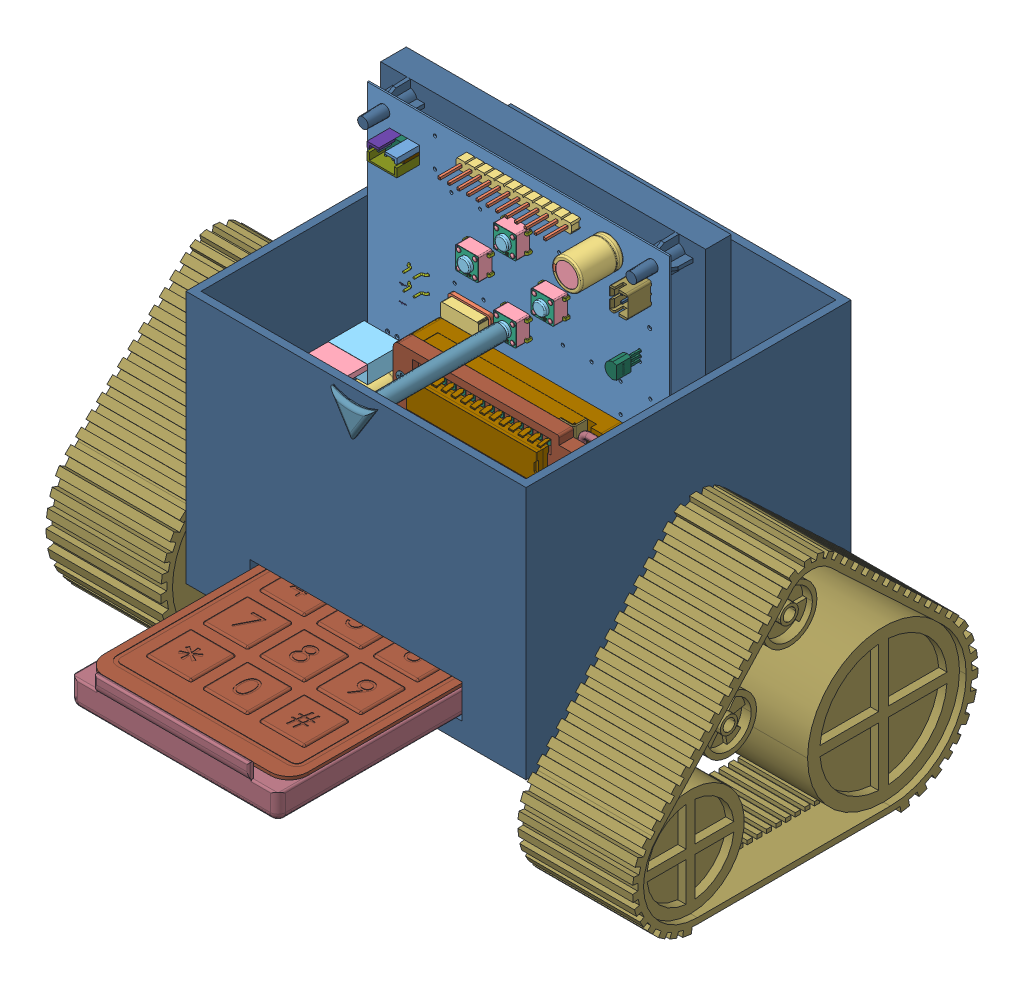
SolidWorks assembly Initial, configuration Default. Lengths in mm.
Overall size (155.25 120.58 135.91).
171 component instances, 50 part files, 12 mates.
Components (placement in the parent):
- Clock PCB.step-1: Clock PCB.step [Default] at (-3.837 -6.133 58.5856) size (81.95 80 25.5)
  - Board.step-1: Board.step [Default] at origin size (80 80 0.41)
    - Open CASCADE STEP translator 6.8 1.1.1.step-1: Open CASCADE STEP translator 6.8 1.1.1.step [Default] at (0 0 -0.4115) size (80 80 0.41)
  - XTAL1.step-1: XTAL1.step [Default] at origin size (11.36 4.66 3.61)
    - 6606830048.step-1: 6606830048.step [Default] at (28.0499 41.0499 0) size (11.36 4.66 1.01)
      - Extruded.step-1: Extruded.step [Default] at origin size (11.36 4.66 1.01)
    - 6606829968.step-1: 6606829968.step [Default] at (28.0499 41.0501 1) size (10.05 3.71 2.61)
      - Extruded-0.step-1: Extruded-0.step [Default] at origin size (10.05 3.71 2.61)
  - U2.step-1: U2.step [Default] at origin size (10.5 4.7 16.2)
    - 6606829888.step-1: 6606829888.step [Default] at (7.95 27.55 13.05) size (10.4 1.3 6.65)
      - Extruded-1.step-1: Extruded-1.step [Default] at origin size (10.4 1.3 6.65)
    - 6606829728.step-1: 6606829728.step [Default] at (7.95 25.9 3.5) size (10.5 4.7 9.55)
      - Extruded-2.step-1: Extruded-2.step [Default] at origin size (10.5 4.7 9.55)
  - U1.step-1: U1.step [Default] at origin size (63.7 16.03 14.45)
    - User_Library-ZIF-Socket-28-pin.step-1: User_Library-ZIF-Socket-28-pin.step [Default] at (43.5 28.05 0) x (1 0 0) z (0 0 1) size (63.7 16.03 14.45)
      - Contacts.step-1: Contacts.step [Default] at origin size (34.37 11.24 1.5)
      - Pins001.step-1: Pins001.step [Default] at origin size (33.87 8.47 3)
      - Screw002.step-1: Screw002.step [Default] at origin size (2.8 2.8 2)
      - Bottom-Shape.step-1: Bottom-Shape.step [Default] at origin size (50.4 15.02 8.11)
      - Lever-Tip.step-1: Lever-Tip.step [Default] at origin size (7 4.8 4.8)
      - Top-Shape.step-1: Top-Shape.step [Default] at origin size (50.4 15.02 3.8)
      - Push-Bar.step-1: Push-Bar.step [Default] at origin size (3.85 15.02 3.7)
      - Lever-Bar.step-1: Lever-Bar.step [Default] at origin size (19.2 11.43 1.62)
      - Screw001.step-1: Screw001.step [Default] at origin size (2.8 2.8 2)
  - Q1.step-1: Q1.step [Default] at origin size (3.05 4.08 12.8)
    - BC547-B.step-1: BC547-B.step [Default] at (72 53.1536 7) x (0 1 0) z (0 0 -1) size (4.08 3.05 12.8)
  - P3.step-1: P3.step [Default] at origin size (2.54 10.16 11.54)
    - 61300411121.step-1: 61300411121.step [Default] at (76.2999 22.6001 1.3) x (0 1 0) z (1 0 0) size (10.16 11.54 2.54)
      - 6130xx11121_PIN.step-1: 6130xx11121_PIN.step [Default] at (-3.81 1.5 0) x (1 0 0) z (0 -1 0) size (0.64 0.64 11.54)
      - 6130xx11121_PIN.step-2: 6130xx11121_PIN.step [Default] at (-1.27 1.5 0) x (1 0 0) z (0 -1 0) size (0.64 0.64 11.54)
      - 6130xx11121_PIN.step-3: 6130xx11121_PIN.step [Default] at (1.27 1.5 0) x (1 0 0) z (0 -1 0) size (0.64 0.64 11.54)
      - 6130xx11121_PIN.step-4: 6130xx11121_PIN.step [Default] at (3.81 1.5 0) x (1 0 0) z (0 -1 0) size (0.64 0.64 11.54)
      - 61300411121-3.step-1: 61300411121-3.step [Default] at origin size (10.16 2.54 2.54)
  - P2.step-1: P2.step [Default] at origin size (17.78 2.54 11.54)
    - 61300711121.step-1: 61300711121.step [Default] at (39.9599 3.8999 1.3) x (-1 0 0) z (0 1 0) size (17.78 11.54 2.54)
      - 6130xx11121_PIN-4.step-1: 6130xx11121_PIN-4.step [Default] at (-7.62 1.5 0) x (1 0 0) z (0 -1 0) size (0.64 0.64 11.54)
      - 6130xx11121_PIN-4.step-2: 6130xx11121_PIN-4.step [Default] at (-5.08 1.5 0) x (1 0 0) z (0 -1 0) size (0.64 0.64 11.54)
      - 6130xx11121_PIN-4.step-3: 6130xx11121_PIN-4.step [Default] at (-2.54 1.5 0) x (1 0 0) z (0 -1 0) size (0.64 0.64 11.54)
      - 6130xx11121_PIN-4.step-4: 6130xx11121_PIN-4.step [Default] at (0 1.5 0) x (1 0 0) z (0 -1 0) size (0.64 0.64 11.54)
      - 6130xx11121_PIN-4.step-5: 6130xx11121_PIN-4.step [Default] at (2.54 1.5 0) x (1 0 0) z (0 -1 0) size (0.64 0.64 11.54)
      - 6130xx11121_PIN-4.step-6: 6130xx11121_PIN-4.step [Default] at (5.08 1.5 0) x (1 0 0) z (0 -1 0) size (0.64 0.64 11.54)
      - 6130xx11121_PIN-4.step-7: 6130xx11121_PIN-4.step [Default] at (7.62 1.5 0) x (1 0 0) z (0 -1 0) size (0.64 0.64 11.54)
      - 61300711121-5.step-1: 61300711121-5.step [Default] at origin size (17.78 2.54 2.54)
  - P1.step-1: P1.step [Default] at origin size (30.48 2.54 11.54)
    - 61301211121.step-1: 61301211121.step [Default] at (41.3799 75.6999 1.3) x (-1 0 0) z (0 1 0) size (30.48 11.54 2.54)
      - 6130xx11121_PIN-6.step-1: 6130xx11121_PIN-6.step [Default] at (-13.97 1.5 0) x (1 0 0) z (0 -1 0) size (0.64 0.64 11.54)
      - 6130xx11121_PIN-6.step-2: 6130xx11121_PIN-6.step [Default] at (-11.43 1.5 0) x (1 0 0) z (0 -1 0) size (0.64 0.64 11.54)
      - 6130xx11121_PIN-6.step-3: 6130xx11121_PIN-6.step [Default] at (-8.89 1.5 0) x (1 0 0) z (0 -1 0) size (0.64 0.64 11.54)
      - 6130xx11121_PIN-6.step-4: 6130xx11121_PIN-6.step [Default] at (-6.35 1.5 0) x (1 0 0) z (0 -1 0) size (0.64 0.64 11.54)
      - 6130xx11121_PIN-6.step-5: 6130xx11121_PIN-6.step [Default] at (-3.81 1.5 0) x (1 0 0) z (0 -1 0) size (0.64 0.64 11.54)
      - 6130xx11121_PIN-6.step-6: 6130xx11121_PIN-6.step [Default] at (-1.27 1.5 0) x (1 0 0) z (0 -1 0) size (0.64 0.64 11.54)
      - 6130xx11121_PIN-6.step-7: 6130xx11121_PIN-6.step [Default] at (1.27 1.5 0) x (1 0 0) z (0 -1 0) size (0.64 0.64 11.54)
      - 6130xx11121_PIN-6.step-8: 6130xx11121_PIN-6.step [Default] at (3.81 1.5 0) x (1 0 0) z (0 -1 0) size (0.64 0.64 11.54)
      - 6130xx11121_PIN-6.step-9: 6130xx11121_PIN-6.step [Default] at (6.35 1.5 0) x (1 0 0) z (0 -1 0) size (0.64 0.64 11.54)
      - 6130xx11121_PIN-6.step-10: 6130xx11121_PIN-6.step [Default] at (8.89 1.5 0) x (1 0 0) z (0 -1 0) size (0.64 0.64 11.54)
      - 6130xx11121_PIN-6.step-11: 6130xx11121_PIN-6.step [Default] at (11.43 1.5 0) x (1 0 0) z (0 -1 0) size (0.64 0.64 11.54)
      - 6130xx11121_PIN-6.step-12: 6130xx11121_PIN-6.step [Default] at (13.97 1.5 0) x (1 0 0) z (0 -1 0) size (0.64 0.64 11.54)
      - 61301211121-7.step-1: 61301211121-7.step [Default] at origin size (30.48 2.54 2.54)
  - KEY5.step-1: KEY5.step [Default] at origin size (7.8 5.99 8.11)
    - Switch_TE_1825910-2_eec.step-1: Switch_TE_1825910-2_eec.step [Default] at (68.1 13.85 0) size (7.8 5.99 8.11)
      - Body.step-1: Body.step [Default] at (0 0 4.3) x (0 -1 0) z (0 0 1) size (5.99 5.99 3.9)
      - button.step-1: button.step [Default] at (0 0 4.3) x (0 -1 0) z (0 0 1) size (3.51 3.51 1.1)
      - cover.step-1: cover.step [Default] at (0 0 4.3) x (0 -1 0) z (0 0 1) size (5.99 5.99 0.1)
      - leads.step-1: leads.step [Default] at (0 0 4.3) x (0 -1 0) z (0 0 1) size (5.21 7.8 4.81)
      - circle.step-1: circle.step [Default] at (-2.6803 2.6863 3.6) size (0.4 0.4 0)
      - TE_Connectivity.step-1: TE_Connectivity.step [Default] at (-0.1925 -2.4218 3.6) size (2.27 0.85 0.01)
  - KEY4.step-1: KEY4.step [Default] at origin size (7.8 5.99 8.11)
    - Switch_TE_1825910-2_eec.step-1: Switch_TE_1825910-2_eec.step [Default] at (50 55 0) size (7.8 5.99 8.11)
      - Body.step-1: Body.step [Default] at (0 0 4.3) x (0 -1 0) z (0 0 1) size (5.99 5.99 3.9)
      - button.step-1: button.step [Default] at (0 0 4.3) x (0 -1 0) z (0 0 1) size (3.51 3.51 1.1)
      - cover.step-1: cover.step [Default] at (0 0 4.3) x (0 -1 0) z (0 0 1) size (5.99 5.99 0.1)
      - leads.step-1: leads.step [Default] at (0 0 4.3) x (0 -1 0) z (0 0 1) size (5.21 7.8 4.81)
      - circle.step-1: circle.step [Default] at (-2.6803 2.6863 3.6) size (0.4 0.4 0)
      - TE_Connectivity.step-1: TE_Connectivity.step [Default] at (-0.1925 -2.4218 3.6) size (2.27 0.85 0.01)
  - KEY3.step-1: KEY3.step [Default] at origin size (7.8 5.99 8.11)
    - Switch_TE_1825910-2_eec.step-1: Switch_TE_1825910-2_eec.step [Default] at (30 55 0) size (7.8 5.99 8.11)
      - Body.step-1: Body.step [Default] at (0 0 4.3) x (0 -1 0) z (0 0 1) size (5.99 5.99 3.9)
      - button.step-1: button.step [Default] at (0 0 4.3) x (0 -1 0) z (0 0 1) size (3.51 3.51 1.1)
      - cover.step-1: cover.step [Default] at (0 0 4.3) x (0 -1 0) z (0 0 1) size (5.99 5.99 0.1)
      - leads.step-1: leads.step [Default] at (0 0 4.3) x (0 -1 0) z (0 0 1) size (5.21 7.8 4.81)
      - circle.step-1: circle.step [Default] at (-2.6803 2.6863 3.6) size (0.4 0.4 0)
      - TE_Connectivity.step-1: TE_Connectivity.step [Default] at (-0.1925 -2.4218 3.6) size (2.27 0.85 0.01)
  - KEY2.step-1: KEY2.step [Default] at origin size (7.8 5.99 8.11)
    - Switch_TE_1825910-2_eec.step-1: Switch_TE_1825910-2_eec.step [Default] at (40 45 0) size (7.8 5.99 8.11)
      - Body.step-1: Body.step [Default] at (0 0 4.3) x (0 -1 0) z (0 0 1) size (5.99 5.99 3.9)
      - button.step-1: button.step [Default] at (0 0 4.3) x (0 -1 0) z (0 0 1) size (3.51 3.51 1.1)
      - cover.step-1: cover.step [Default] at (0 0 4.3) x (0 -1 0) z (0 0 1) size (5.99 5.99 0.1)
      - leads.step-1: leads.step [Default] at (0 0 4.3) x (0 -1 0) z (0 0 1) size (5.21 7.8 4.81)
      - circle.step-1: circle.step [Default] at (-2.6803 2.6863 3.6) size (0.4 0.4 0)
      - TE_Connectivity.step-1: TE_Connectivity.step [Default] at (-0.1925 -2.4218 3.6) size (2.27 0.85 0.01)
  - KEY1.step-1: KEY1.step [Default] at origin size (7.8 5.99 8.11)
    - Switch_TE_1825910-2_eec.step-1: Switch_TE_1825910-2_eec.step [Default] at (40 65 0) size (7.8 5.99 8.11)
      - Body.step-1: Body.step [Default] at (0 0 4.3) x (0 -1 0) z (0 0 1) size (5.99 5.99 3.9)
      - button.step-1: button.step [Default] at (0 0 4.3) x (0 -1 0) z (0 0 1) size (3.51 3.51 1.1)
      - cover.step-1: cover.step [Default] at (0 0 4.3) x (0 -1 0) z (0 0 1) size (5.99 5.99 0.1)
      - leads.step-1: leads.step [Default] at (0 0 4.3) x (0 -1 0) z (0 0 1) size (5.21 7.8 4.81)
      - circle.step-1: circle.step [Default] at (-2.6803 2.6863 3.6) size (0.4 0.4 0)
      - TE_Connectivity.step-1: TE_Connectivity.step [Default] at (-0.1925 -2.4218 3.6) size (2.27 0.85 0.01)
  - JST2.step-1: JST2.step [Default] at origin size (4.7 6 10.05)
    - Conn_TE_Connectivity_440054-2_eec.step-1: Conn_TE_Connectivity_440054-2_eec.step [Default] at (72.85 68.85 0) x (0 -1 0) z (0 0 1) size (6 4.7 10.05)
      - 1.step-1: 1.step [Default] at (0 -0.6 6.05) size (2.5 2.35 8.8)
      - 2.step-1: 2.step [Default] at (0 -0.6 6.05) size (0.9 0.1 1.08)
      - 3.step-1: 3.step [Default] at (0 -0.6 6.05) size (6 4.7 6.35)
      - TE_connectivity_Logo_1_(2).step-1: TE_connectivity_Logo_1_(2).step [Default] at (2.901 6.9182 0.6322) x (0 -1 0) z (1 0 0) size (1.49 0.53 0.1)
  - JST1.step-1: JST1.step [Default] at origin size (6 4.7 10.05)
    - Conn_TE_Connectivity_440054-2_eec.step-1: Conn_TE_Connectivity_440054-2_eec.step [Default] at (10.55 4.25 0) x (-1 0 0) z (0 0 1) size (6 4.7 10.05)
      - 1.step-1: 1.step [Default] at (0 -0.6 6.05) size (2.5 2.35 8.8)
      - 2.step-1: 2.step [Default] at (0 -0.6 6.05) size (0.9 0.1 1.08)
      - 3.step-1: 3.step [Default] at (0 -0.6 6.05) size (6 4.7 6.35)
      - TE_connectivity_Logo_1_(2).step-1: TE_connectivity_Logo_1_(2).step [Default] at (2.901 6.9182 0.6322) x (0 -1 0) z (1 0 0) size (1.49 0.53 0.1)
  - JST3.step-1: JST3.step [Default] at origin size (7.9 4.5 9.4)
    - 6606829248.step-1: 6606829248.step [Default] at (11.9 70.55 -3.4) size (0.5 0.5 8.45)
      - Extruded-8.step-1: Extruded-8.step [Default] at origin size (0.5 0.5 8.45)
    - 6606829248.step-2: 6606829248.step [Default] at (7.9 70.55 -3.4) size (0.5 0.5 8.45)
      - Extruded-8.step-1: Extruded-8.step [Default] at origin size (0.5 0.5 8.45)
    - 6606829248.step-3: 6606829248.step [Default] at (9.9 70.55 -3.4) size (0.5 0.5 8.45)
      - Extruded-8.step-1: Extruded-8.step [Default] at origin size (0.5 0.5 8.45)
    - 6606828928.step-1: 6606828928.step [Default] at (9.9 70.2 0) size (6.6 4.1 1.75)
      - Extruded-9.step-1: Extruded-9.step [Default] at origin size (6.6 4.1 1.75)
    - 6606828768.step-1: 6606828768.step [Default] at (9.9 68.875 0) size (7.9 2.25 6)
      - Extruded-10.step-1: Extruded-10.step [Default] at origin size (7.9 2.25 6)
    - 6606828608.step-1: 6606828608.step [Default] at (7.525 71.525 0) size (3.15 1.45 6)
      - Extruded-11.step-1: Extruded-11.step [Default] at origin size (3.15 1.45 6)
    - 6606828448.step-1: 6606828448.step [Default] at (6.275 70.4 0) size (0.65 0.8 4.1)
      - Extruded-12.step-1: Extruded-12.step [Default] at origin size (0.65 0.8 4.1)
    - 6606828448.step-2: 6606828448.step [Default] at (13.525 70.4 0) size (0.65 0.8 4.1)
      - Extruded-12.step-1: Extruded-12.step [Default] at origin size (0.65 0.8 4.1)
    - 6606828208.step-1: 6606828208.step [Default] at (12.275 71.525 0) size (3.15 1.45 6)
      - Extruded-13.step-1: Extruded-13.step [Default] at origin size (3.15 1.45 6)
  - C6.step-1: C6.step [Default] at origin size (8 8 14.5)
    - Aluminum_electrolytic_capacitor_radial_D8_H11.5_PinD0.6_Pitch3.5_nominal_black.step-1: Aluminum_electrolytic_capacitor_radial_D8_H11.5_PinD0.6_Pitch3.5_nominal_black.step [Default] at (64.35 73.55 0) x (-1 0 0) z (0 0 1) size (1.1 2.07 11.1)
    - Aluminum_electrolytic_capacitor_radial_D8_H11.5_PinD0.6_Pitch3.5_nominal_black-14.step-1: Aluminum_electrolytic_capacitor_radial_D8_H11.5_PinD0.6_Pitch3.5_nominal_black-14.step [Default] at (64.35 73.55 0) x (-1 0 0) z (0 0 1) size (7.86 8 11.1)
    - Aluminum_electrolytic_capacitor_radial_D8_H11.5_PinD0.6_Pitch3.5_nominal_black-15.step-1: Aluminum_electrolytic_capacitor_radial_D8_H11.5_PinD0.6_Pitch3.5_nominal_black-15.step [Default] at (64.35 73.55 0) x (-1 0 0) z (0 0 1) size (7.8 7.8 10.9)
    - Aluminum_electrolytic_capacitor_radial_D8_H11.5_PinD0.6_Pitch3.5_nominal_black-16.step-1: Aluminum_electrolytic_capacitor_radial_D8_H11.5_PinD0.6_Pitch3.5_nominal_black-16.step [Default] at (64.35 73.55 0) x (-1 0 0) z (0 0 1) size (7.4 7.4 1.6)
    - Aluminum_electrolytic_capacitor_radial_D8_H11.5_PinD0.6_Pitch3.5_nominal_black-17.step-1: Aluminum_electrolytic_capacitor_radial_D8_H11.5_PinD0.6_Pitch3.5_nominal_black-17.step [Default] at (64.35 73.55 0) x (-1 0 0) z (0 0 1) size (4.1 0.6 3)
  - C5.step-1: C5.step [Default] at origin size (8 8 14.5)
    - Aluminum_electrolytic_capacitor_radial_D8_H11.5_PinD0.6_Pitch3.5_nominal_black.step-1: Aluminum_electrolytic_capacitor_radial_D8_H11.5_PinD0.6_Pitch3.5_nominal_black.step [Default] at (65.05 5.25 0) size (1.1 2.07 11.1)
    - Aluminum_electrolytic_capacitor_radial_D8_H11.5_PinD0.6_Pitch3.5_nominal_black-14.step-1: Aluminum_electrolytic_capacitor_radial_D8_H11.5_PinD0.6_Pitch3.5_nominal_black-14.step [Default] at (65.05 5.25 0) size (7.86 8 11.1)
    - Aluminum_electrolytic_capacitor_radial_D8_H11.5_PinD0.6_Pitch3.5_nominal_black-15.step-1: Aluminum_electrolytic_capacitor_radial_D8_H11.5_PinD0.6_Pitch3.5_nominal_black-15.step [Default] at (65.05 5.25 0) size (7.8 7.8 10.9)
    - Aluminum_electrolytic_capacitor_radial_D8_H11.5_PinD0.6_Pitch3.5_nominal_black-16.step-1: Aluminum_electrolytic_capacitor_radial_D8_H11.5_PinD0.6_Pitch3.5_nominal_black-16.step [Default] at (65.05 5.25 0) size (7.4 7.4 1.6)
    - Aluminum_electrolytic_capacitor_radial_D8_H11.5_PinD0.6_Pitch3.5_nominal_black-17.step-1: Aluminum_electrolytic_capacitor_radial_D8_H11.5_PinD0.6_Pitch3.5_nominal_black-17.step [Default] at (65.05 5.25 0) size (4.1 0.6 3)
  - C4.step-1: C4.step [Default] at origin size (5.99 5.99 8.89)
    - Cap_Murata_RCE5C2A3R0C0K1H03B_eec.step-1: Cap_Murata_RCE5C2A3R0C0K1H03B_eec.step [Default] at (13.7 39.4 0) x (1 0 0) z (0 0 1) size (5.99 5.99 8.89)
      - Body.step-1: Body.step [Default] at origin size (5.99 5.99 3.9)
      - leads-18.step-1: leads-18.step [Default] at origin size (5.5 0.5 6.65)
      - logo.step-1: logo.step [Default] at (0 -1.25 8.5) x (1 0 0) z (0 -1 0) size (1.98 0.46 0.01)
  - C3.step-1: C3.step [Default] at origin size (5.99 5.99 8.89)
    - Cap_Murata_RCE5C2A3R0C0K1H03B_eec.step-1: Cap_Murata_RCE5C2A3R0C0K1H03B_eec.step [Default] at (13.65 43.7 0) x (1 0 0) z (0 0 1) size (5.99 5.99 8.89)
      - Body.step-1: Body.step [Default] at origin size (5.99 5.99 3.9)
      - leads-18.step-1: leads-18.step [Default] at origin size (5.5 0.5 6.65)
      - logo.step-1: logo.step [Default] at (0 -1.25 8.5) x (1 0 0) z (0 -1 0) size (1.98 0.46 0.01)
  - C2.step-1: C2.step [Default] at origin size (8 8 14.5)
    - Aluminum_electrolytic_capacitor_radial_D8_H11.5_PinD0.6_Pitch3.5_nominal_black.step-1: Aluminum_electrolytic_capacitor_radial_D8_H11.5_PinD0.6_Pitch3.5_nominal_black.step [Default] at (17.55 14.1 0) size (1.1 2.07 11.1)
    - Aluminum_electrolytic_capacitor_radial_D8_H11.5_PinD0.6_Pitch3.5_nominal_black-14.step-1: Aluminum_electrolytic_capacitor_radial_D8_H11.5_PinD0.6_Pitch3.5_nominal_black-14.step [Default] at (17.55 14.1 0) size (7.86 8 11.1)
    - Aluminum_electrolytic_capacitor_radial_D8_H11.5_PinD0.6_Pitch3.5_nominal_black-15.step-1: Aluminum_electrolytic_capacitor_radial_D8_H11.5_PinD0.6_Pitch3.5_nominal_black-15.step [Default] at (17.55 14.1 0) size (7.8 7.8 10.9)
    - Aluminum_electrolytic_capacitor_radial_D8_H11.5_PinD0.6_Pitch3.5_nominal_black-16.step-1: Aluminum_electrolytic_capacitor_radial_D8_H11.5_PinD0.6_Pitch3.5_nominal_black-16.step [Default] at (17.55 14.1 0) size (7.4 7.4 1.6)
    - Aluminum_electrolytic_capacitor_radial_D8_H11.5_PinD0.6_Pitch3.5_nominal_black-17.step-1: Aluminum_electrolytic_capacitor_radial_D8_H11.5_PinD0.6_Pitch3.5_nominal_black-17.step [Default] at (17.55 14.1 0) size (4.1 0.6 3)
  - C1.step-1: C1.step [Default] at origin size (8 8 14.5)
    - Aluminum_electrolytic_capacitor_radial_D8_H11.5_PinD0.6_Pitch3.5_nominal_black.step-1: Aluminum_electrolytic_capacitor_radial_D8_H11.5_PinD0.6_Pitch3.5_nominal_black.step [Default] at (7.05 14.5 0) size (1.1 2.07 11.1)
    - Aluminum_electrolytic_capacitor_radial_D8_H11.5_PinD0.6_Pitch3.5_nominal_black-14.step-1: Aluminum_electrolytic_capacitor_radial_D8_H11.5_PinD0.6_Pitch3.5_nominal_black-14.step [Default] at (7.05 14.5 0) size (7.86 8 11.1)
    - Aluminum_electrolytic_capacitor_radial_D8_H11.5_PinD0.6_Pitch3.5_nominal_black-15.step-1: Aluminum_electrolytic_capacitor_radial_D8_H11.5_PinD0.6_Pitch3.5_nominal_black-15.step [Default] at (7.05 14.5 0) size (7.8 7.8 10.9)
    - Aluminum_electrolytic_capacitor_radial_D8_H11.5_PinD0.6_Pitch3.5_nominal_black-16.step-1: Aluminum_electrolytic_capacitor_radial_D8_H11.5_PinD0.6_Pitch3.5_nominal_black-16.step [Default] at (7.05 14.5 0) size (7.4 7.4 1.6)
    - Aluminum_electrolytic_capacitor_radial_D8_H11.5_PinD0.6_Pitch3.5_nominal_black-17.step-1: Aluminum_electrolytic_capacitor_radial_D8_H11.5_PinD0.6_Pitch3.5_nominal_black-17.step [Default] at (7.05 14.5 0) size (4.1 0.6 3)
  - Free-Models.step-1: Free-Models.step [Default] at origin size (34.6 9.68 7.3)
    - atmega328p-pu.step-1: atmega328p-pu.step [Default] at (59.217 28 11) x (-1 0 0) z (0 1 0) size (34.6 7.3 9.68)
- Part46^Initial-1: Part46^Initial [Default] at origin size (90 95.83 86) (virtual)
- Matrix Keypad 12 Key (4X3)-3: Matrix Keypad 12 Key (4X3) [Default] at (36.3513 -10.233 107.9222) x (1 0 0) z (0 1 0) size (54 77 1.31)
- wheel 2-2: wheel 2 [Default] at (-15.3292 -22.5914 32.4684) size (46.7 70.49 91.39)
- wheel 2-5: wheel 2 [Default] at (87.7552 -22.5914 88.1188) x (-1 0 0) z (0 0 -1) size (46.7 70.49 91.39)
- Part4^Initial-1: Part4^Initial [Default] at (36.3513 -10.233 107.9222) x (-1 0 0) z (0 -1 0) size (55 82.09 11) (virtual)
- Part5^Initial-1: Part5^Initial [Default] at (0 0 101.5856) size (12.45 10.37 39.83) (virtual)
Mates (geometry in assembly coordinates):
- Lock3: lock: unknown of Part46^Initial-1; unknown of wheel 2-2
- InPlace1: in place: plane of ? through (70.3473 -28.3571 185.2121) normal (0 -1 0); plane of ? through (0 -28.3571 0) normal (0 -1 0); moOrthogonalPlaneRef_w of ? through (70.3473 -28.3571 185.2121) normal (0 -1 0); plane of ? through (0 -28.3571 0) normal (0 0 -1); plane of ? through (70.3473 -28.3571 185.2121) normal (0 -1 0); plane of ? through (0 -28.3571 0) normal (-1 0 0); plane of Matrix Keypad 12 Key (4X3)-3 through (36.3513 -10.233 107.9222) normal (0 -1 0); unknown of Part4^Initial-1
- Coincident8: coincident aligned: plane of Matrix Keypad 12 Key (4X3)-3; plane of Part4^Initial-1
- Coincident9: coincident aligned: moOrthogonalPlaneRef_w of Matrix Keypad 12 Key (4X3)-3 through (36.3513 -10.233 107.9222) normal (0 0 -1); plane of Part4^Initial-1 through (36.3513 -10.233 107.9222) normal (0 0 -1)
- Coincident10: coincident anti-aligned: moOrthogonalPlaneRef_w of Matrix Keypad 12 Key (4X3)-3 through (36.3513 -10.233 107.9222) normal (1 0 0); plane of Part4^Initial-1 through (36.3513 -10.233 107.9222) normal (-1 0 0)
- Parallel2: parallel anti-aligned: plane of Part46^Initial-1 through (8.213 -6.233 21.5856) normal (1 0 0); plane of Part4^Initial-1 through (8.8513 -17.233 149.8792) normal (-1 0 0)
- Parallel3: parallel anti-aligned: plane of Part46^Initial-1 through (64.213 -6.233 21.5856) normal (-1 0 0); plane of Part4^Initial-1 through (63.8513 -17.233 149.8792) normal (1 0 0)
- Distance1: distance = 0 mm anti-aligned: plane of Part4^Initial-1 through (36.3513 -17.233 107.9222) normal (0 -1 0); plane of Part46^Initial-1 through (6.213 -17.233 21.5856) normal (0 1 0)
- InPlace2: in place: plane of Part46^Initial-1 through (0 0 101.5856) normal (0 0 1); plane of Part5^Initial-1 through (0 0 101.5856) normal (0 0 1); plane of Part46^Initial-1 through (0 0 101.5856) normal (0 0 1); plane of Part5^Initial-1 through (0 0 101.5856) normal (0 1 0); plane of Part46^Initial-1 through (0 0 101.5856) normal (0 0 1); plane of Part5^Initial-1 through (0 0 101.5856) normal (1 0 0); plane of Part46^Initial-1 through (0 0 101.5856) normal (0 0 1); unknown of Part5^Initial-1
- Coincident14: coincident aligned: plane of Part46^Initial-1; plane of Part5^Initial-1
- Coincident15: coincident aligned: moOrthogonalPlaneRef_w of Part46^Initial-1 through (0 0 101.5856) normal (0 1 0); plane of Part5^Initial-1 through (0 0 101.5856) normal (0 1 0)
- Coincident16: coincident anti-aligned: moOrthogonalPlaneRef_w of Part46^Initial-1 through (0 0 101.5856) normal (-1 0 0); plane of Part5^Initial-1 through (0 0 101.5856) normal (1 0 0)
